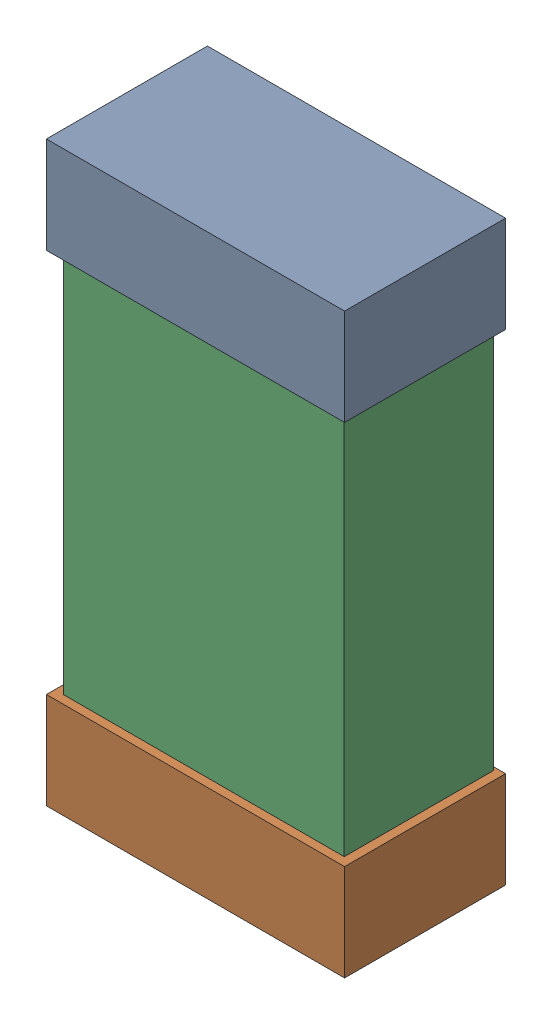
SolidWorks assembly C32, configuration Default. Lengths in mm.
Overall size (0.85 1.65 0.46).
6 component instances, 2 part files, 0 mates.
Components (placement in the parent):
- 432138512_58-1: 432138512_58 [Default] at (17.3802 59.2538 -0.8715) size (0.85 0.28 0.46)
  - Extruded-1: Extruded [Default] at origin size (0.85 0.28 0.46)
- 432138512_59-1: 432138512_59 [Default] at (17.3802 57.8822 -0.8715) size (0.85 0.28 0.46)
  - Extruded-1: Extruded [Default] at origin size (0.85 0.28 0.46)
- 432124816_29-1: 432124816_29 [Default] at (17.3802 58.568 -0.8615) size (0.8 1.5 0.42)
  - Extruded (1)-1: Extruded (1) [Default] at origin size (0.8 1.5 0.42)
